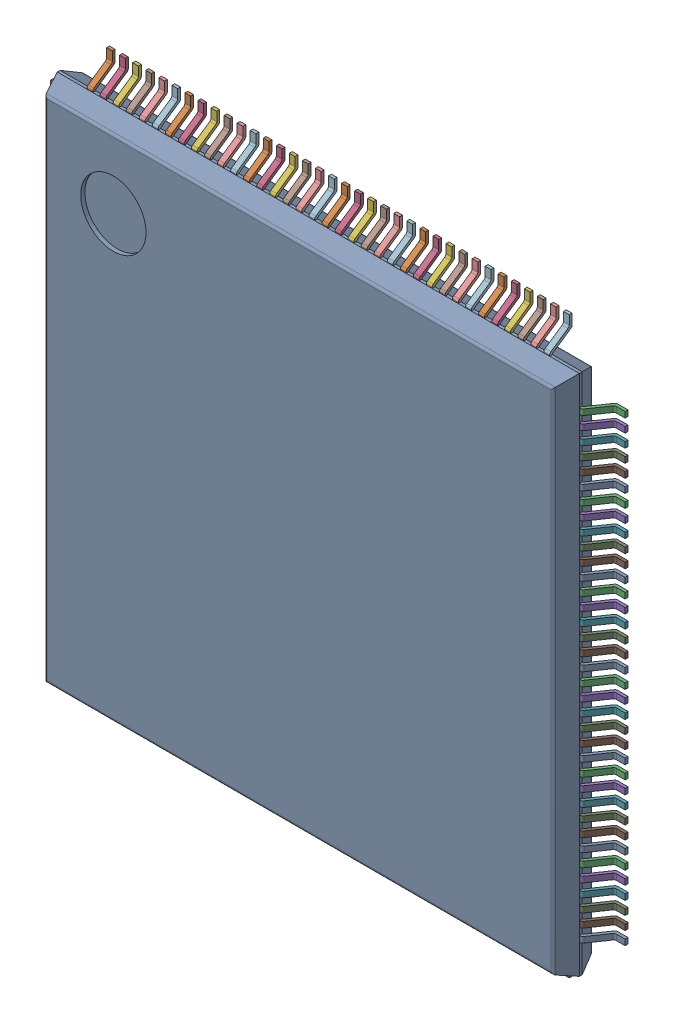
SolidWorks assembly IC1_1.step, configuration Default. Lengths in mm.
Overall size (22 22 1.6).
4 component instances, 3 part files, 0 mates.
Components (placement in the parent):
- 6348794688_1.step-3: 6348794688_1.step [Default] at (417.529 276.576 0) x (1 0 0) z (0 0 1) size (22 22 1.6)
  - Body-1211_1.step-5: Body-1211_1.step [Default] at origin size (20 20 1.5)
  - PinsArrayLR-1212_1.step-5: PinsArrayLR-1212_1.step [Default] at origin size (22 17.72 0.86)
  - PinsArrayTB_1.step-5: PinsArrayTB_1.step [Default] at origin size (17.72 22 0.86)
